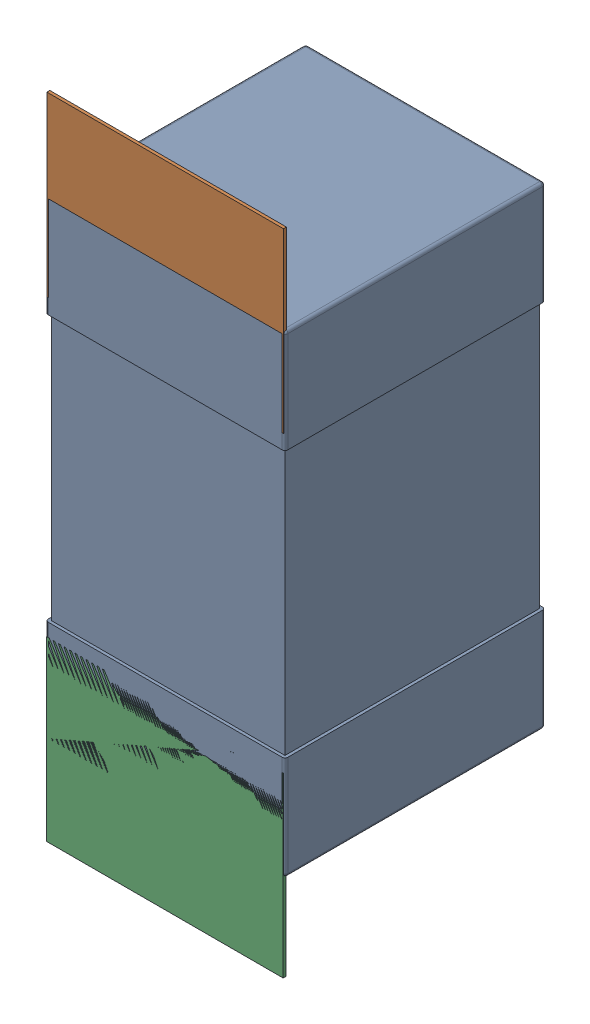
SolidWorks assembly C77, configuration Défaut. Lengths in mm.
Overall size (0.81 2.19 0.88).
5 component instances, 2 part files, 0 mates.
Components (placement in the parent):
- 0603_C-1: 0603_C [Défaut] at (14.5735 -9.4036 -2.0818) x (0 1 0) z (0 0 -1) size (1.6 0.81 0.88)
- 8260087904-1: 8260087904 [Défaut] at (14.5735 -8.1536 -2.0918) size (0.8 0.6 0.01)
  - Extruded_1211-1: Extruded_1211 [Défaut] at origin size (0.8 0.6 0.01)
- 8260087904-2: 8260087904 [Défaut] at (14.5722 -9.7485 -2.0918) size (0.8 0.6 0.01)
  - Extruded_1211-1: Extruded_1211 [Défaut] at origin size (0.8 0.6 0.01)
